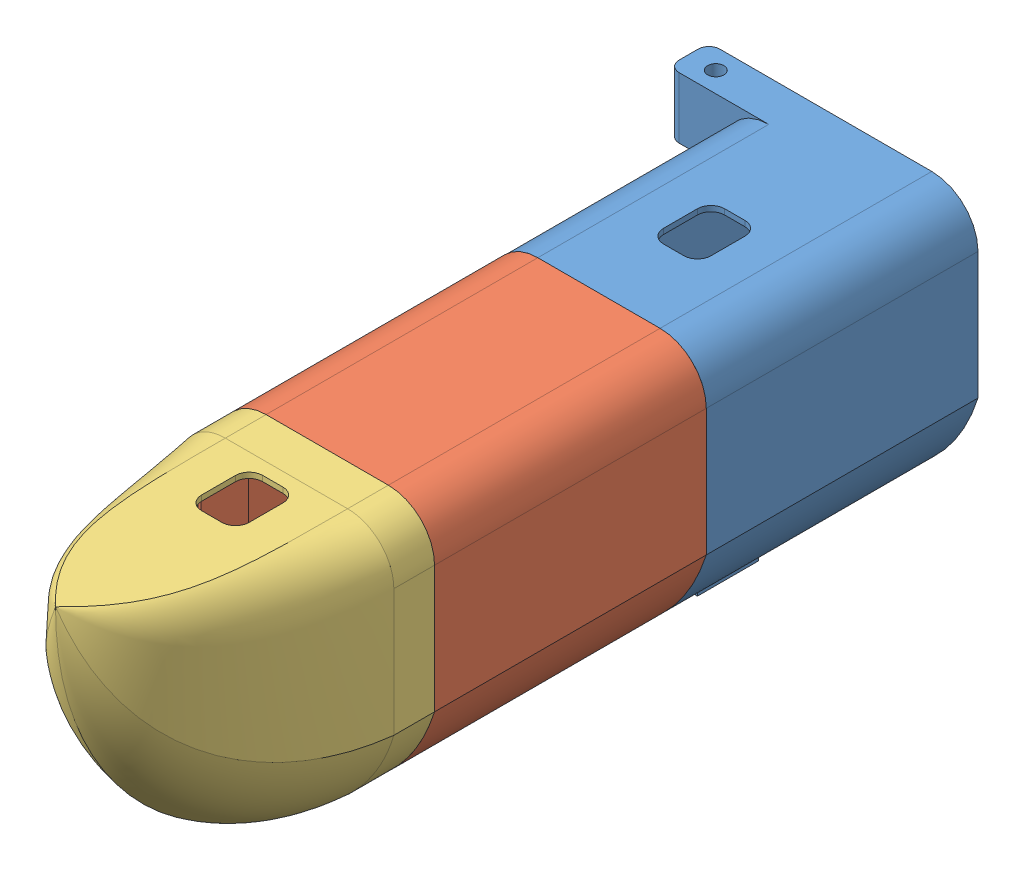
SolidWorks assembly Assemblagehull1, configuration Défaut. Lengths in mm.
Overall size (203.18 223.75 607.68).
3 component instances, 3 part files, 6 mates.
Components (placement in the parent):
- body_back_2-1: body_back_2 [Défaut] at (59.9179 -48.2398 110) size (198 212 220)
- body_mid-1: body_mid [Défaut] at (59.9179 -48.2398 310) size (158 208.49 220)
- body_front-1: body_front [Défaut] at (59.9179 -48.2398 510) size (168.2 223.75 207.68)
Mates (geometry in assembly coordinates):
- Coïncidente1: coincident anti-aligned: plane of body_back_2-1 through (-22.7316 33.2862 310) normal (0 0 1); plane of body_mid-1 through (-22.7316 33.2862 310) normal (0 0 -1)
- Coïncidente2: coincident anti-aligned: plane of body_back_2-1 through (-142.7316 -59.4138 295) normal (-1 0 0); plane of body_mid-1 through (-142.7316 -59.4138 510) normal (1 0 0)
- Coaxiale1: concentric anti-aligned: cylinder of body_back_2-1 through (-226.3429 170.8066 295) axis (0 0 1) radius 346.015; cylinder of body_mid-1 through (-226.3429 170.8066 510) axis (0 0 -1) radius 346.015
- Coïncidente3: coincident: plane of body_mid-1 through (7.2684 33.2862 495) normal (1 0 0); plane of body_front-1 through (7.2684 -59.4138 540) normal (-1 0 0)
- Coïncidente4: coincident: plane of body_mid-1 through (-22.7316 33.2862 510) normal (0 0 1); plane of body_front-1 through (-22.7316 33.2862 510) normal (0 0 -1)
- Coaxiale2: concentric anti-aligned: cylinder of body_mid-1 through (-226.3429 170.8066 495) axis (0 0 1) radius 346.015; cylinder of body_front-1 through (-226.3429 170.8066 540) axis (0 0 -1) radius 346.015
